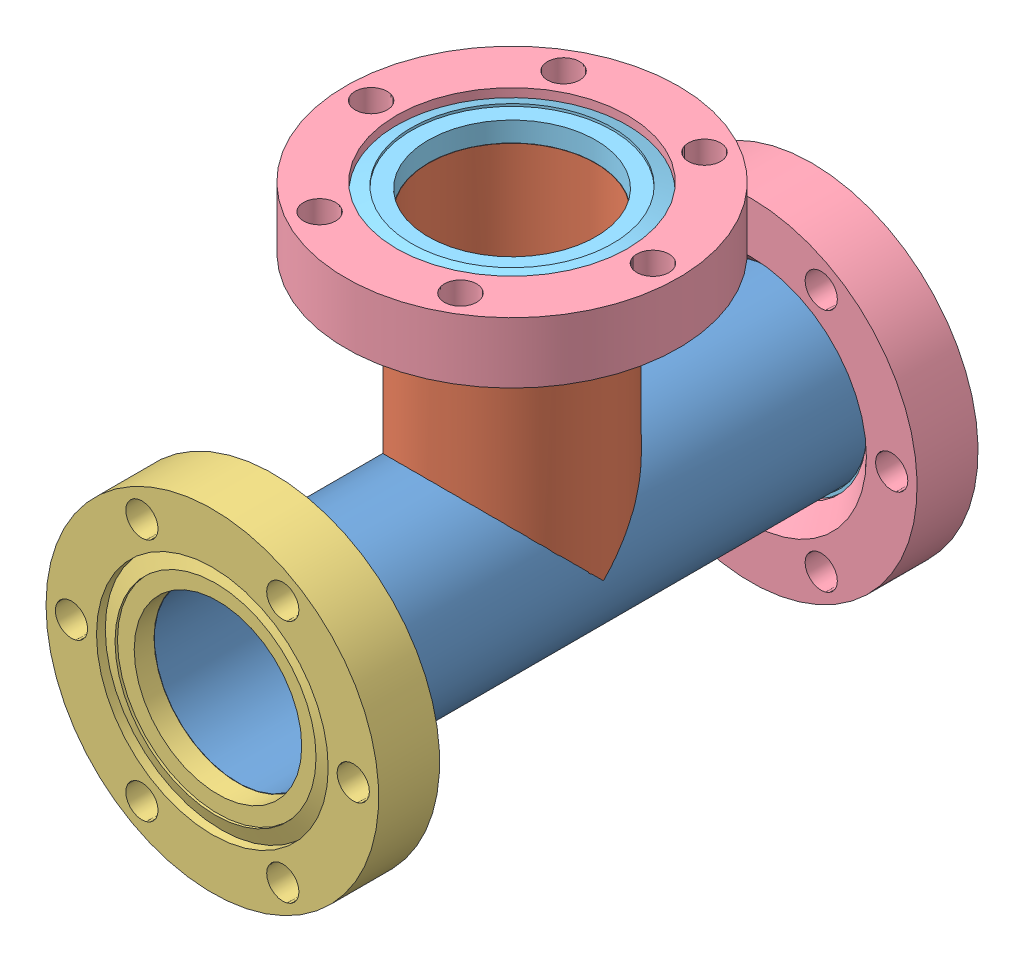
SolidWorks assembly 404002(pull), configuration Default. Lengths in mm.
Overall size (69.34 97.13 124.92).
9 component instances, 5 part files, 0 mates.
Components (placement in the parent):
- 404002-001_pull-1: 404002-001_pull [Default] at origin size (38.1 38.1 114.3)
- 404002-002_pull-1: 404002-002_pull [Default] at (0 0 57.15) x (-1 0 0) z (0 1 0) size (38.1 38.1 58.86)
- 110014 (2.75 X 1.5 NR)_pull-1: 110014 (2.75 X 1.5 NR)_pull [Default] at (0 0 113.2586) x (0 0 1) z (-1 0 0) size (12.7 69.34 69.34)
- 100014 (2.75 X 1.5 R)_pull-1: 100014 (2.75 X 1.5 R)_pull [Default] at (0 62.4586 57.15) x (0 -1 0) z (1 0 0) size (12.7 69.34 69.34)
  - 100014 (2.75 X 1.5 REC)_pull-1: 100014 (2.75 X 1.5 REC)_pull [Default] at origin size (12.7 69.34 69.34)
  - 100014 (2.75 X 1.5 INS)_pull-1: 100014 (2.75 X 1.5 INS)_pull [Default] at (1.17 0 0) x (1 0 0) z (0 0.994423 -0.105464) size (6.96 48.1 48.1)
- 100014 (2.75 X 1.5 R)_pull-2: 100014 (2.75 X 1.5 R)_pull [Default] at (0 0 -5.3086) x (0 0 1) z (-1 0 0) size (12.7 69.34 69.34)
  - 100014 (2.75 X 1.5 REC)_pull-1: 100014 (2.75 X 1.5 REC)_pull [Default] at origin size (12.7 69.34 69.34)
  - 100014 (2.75 X 1.5 INS)_pull-1: 100014 (2.75 X 1.5 INS)_pull [Default] at (1.17 0 0) x (1 0 0) z (0 0.994423 -0.105464) size (6.96 48.1 48.1)
